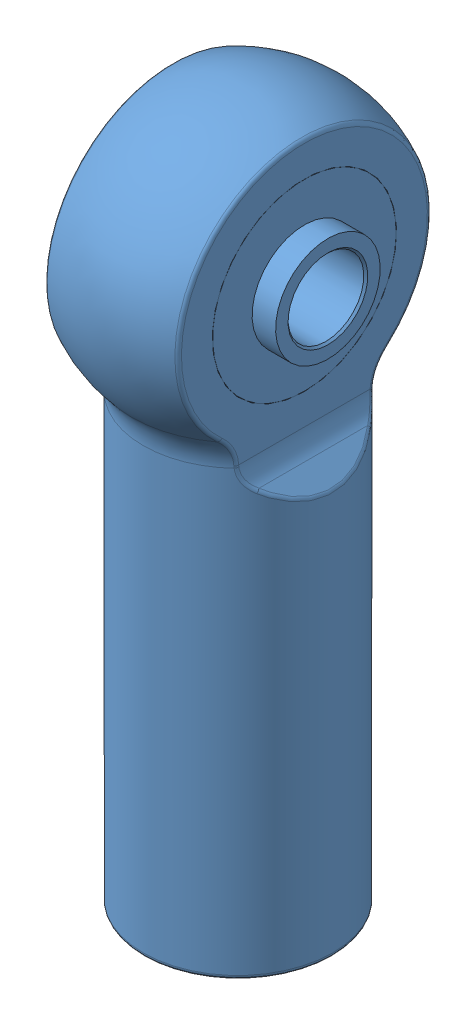
SolidWorks assembly REP4H6, configuration 1_START HERE. Lengths in mm.
Overall size (15.88 62.06 31.13).
2 component instances, 1 part files, 1 mates.
Components (placement in the parent):
- REP4H6-1: REP4H6 [Body] at origin size (15.88 59.54 23.83)
- REP4H6-2: REP4H6 [Ball] x (1 0 0) z (0 0.125816 0.992054) size (15.88 59.54 23.83)
Mates (geometry in assembly coordinates):
- Concentric1: concentric: sphere of REP4H6-1; sphere of REP4H6-2
